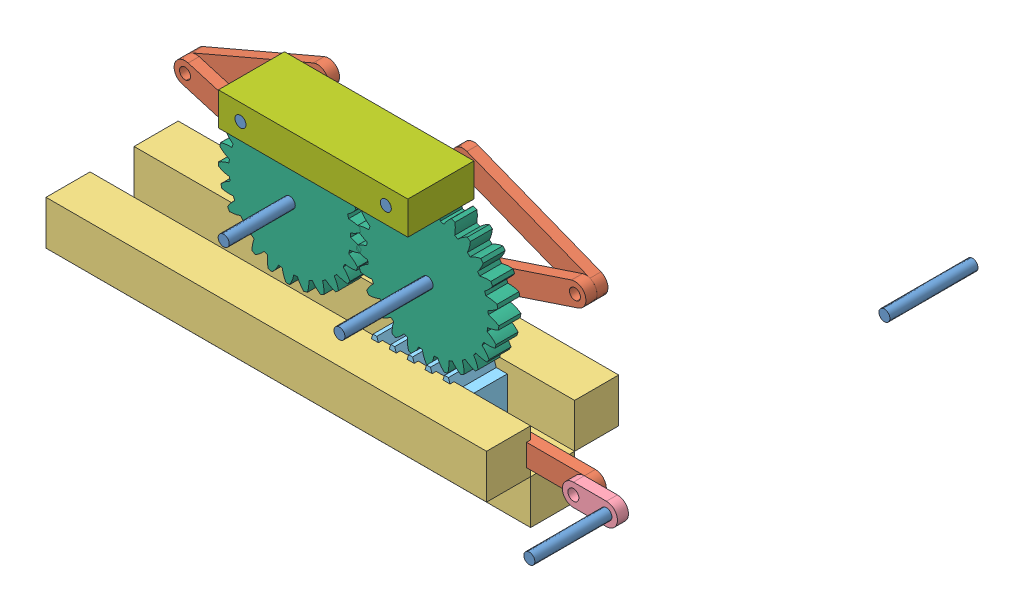
SolidWorks assembly assembly1, configuration Default. Lengths in mm.
Overall size (426.89 177.01 138.77).
17 component instances, 7 part files, 23 mates.
Components (placement in the parent):
- joint_1-1: joint_1 [Default] at (-55.7079 602.4272 -213.8227) x (-0.185168 0.982707 0) z (0 0 -1) size (6.35 6.35 50.8)
- LINK_4-1: LINK_4 [Default] at (-191.5162 473.0256 -183.0038) x (-1 0.000971 0) z (0 0 1) size (88.9 12.7 6.35)
- joint_1-2: joint_1 [Default] at (-172.4724 466.6561 -176.6538) x (-0.995124 -0.09863 0) z (0 0 1) size (6.35 6.35 50.8)
- platform_1-1: platform_1 [Default] at (-478.8705 454.5203 -229.7868) x (0 0 1) z (-0.000738 1 0) size (76.2 254 50.8)
- LINK_4-2: LINK_4 [Default] at (-216.1405 538.28 -199.8563) x (-0.930981 0.365067 0) z (0 0 -1) size (88.9 12.7 6.35)
- LINK_4-3: LINK_4 [Default] at (-441.1342 547.8007 -199.8563) x (0.919324 0.393502 0) z (0 0 -1) size (88.9 12.7 6.35)
- LINK_4-4: LINK_4 [Default] at (-211.8174 538.1665 -193.5063) x (-0.948848 -0.315733 0) z (0 0 -1) size (88.9 12.7 6.35)
- LINK_4-5: LINK_4 [Default] at (-440.4322 535.8725 -199.8563) x (0.959139 -0.282937 0) z (0 0 1) size (88.9 12.7 6.35)
- joint_1-4: joint_1 [Default] at (-365.5491 520.4032 -193.5063) x (0.131558 0.991308 0) z (0 0 1) size (6.35 6.35 50.8)
- joint_1-5: joint_1 [Default] at (-286.1245 520.1328 -180.8063) x (0.649611 0.760266 0) z (0 0 1) size (6.35 6.35 50.8)
- joint_1-6: joint_1 [Default] at (-284.7631 572.0098 -206.2063) x (0.531975 -0.84676 0) z (0 0 1) size (6.35 6.35 50.8)
- joint_1-8: joint_1 [Default] at (-368.583 571.9479 -206.2063) x (0.538835 -0.842411 0) z (0 0 1) size (6.35 6.35 50.8)
- LINK crank_1-2: LINK crank_1 [Default] at (-191.5158 473.0256 -170.3038) x (0.999999 -0.001025 0) z (0 0 -1) size (31.75 12.7 6.35)
- 2 g rack-2: 2 g rack [Default] at (-255.02 454.6856 -176.6538) x (-1 -0.000738 0) z (0 0 -1) size (57.15 28.15 25.4)
- gear new1-1: gear new1 [Default] at (-365.5491 520.4032 -180.8063) x (-0.514078 0.857744 0) z (0 0 -1) size (82.17 82.02 12.7)
- gear new1-2: gear new1 [Default] at (-286.1245 520.1328 -180.8063) x (0.174544 0.984649 0) z (0 0 -1) size (82.17 82.02 12.7)
- lifting-1: lifting [Default] at (-381.276 562.4135 -193.5063) x (1 0.000738 0) z (0 0 1) size (109.22 19.05 38.1)
Mates (geometry in assembly coordinates):
- Coincident17: coincident aligned: circle of LINK_4-2; circle of LINK_4-4
- Coincident19: coincident anti-aligned: circle of LINK_4-3; circle of joint_1-8
- Coincident20: coincident anti-aligned: circle of LINK_4-2; circle of joint_1-6
- Coincident59: coincident anti-aligned: circle of joint_1-2; circle of LINK crank_1-2
- Coincident60: coincident aligned: cylinder of LINK_4-1; cylinder of LINK crank_1-2 through (-191.5224 466.6757 -176.6538) axis (0 0 1) radius 3.175
- Coincident69: coincident anti-aligned: plane of LINK_4-1 through (-191.5161 473.0248 -176.6538) normal (0 0 1); plane of LINK crank_1-2 through (-191.5161 473.0248 -176.6538) normal (0 0 -1)
- Coincident82: coincident anti-aligned: circle of LINK_4-3; circle of LINK_4-5
- Coincident83: coincident anti-aligned: circle of joint_1-4; circle of gear new1-1
- Coincident84: coincident anti-aligned: circle of joint_1-5; circle of gear new1-2
- Coincident85: coincident anti-aligned: circle of LINK_4-1; circle of 2 g rack-2
- Coincident86: coincident anti-aligned: plane of platform_1-1 through (-478.8705 454.5203 -229.7868) normal (-0.000738 1 0); plane of 2 g rack-2 through (-255.02 454.6856 -202.0538) normal (0.000738 -1 0)
- Coincident87: coincident aligned: circle of LINK_4-4; circle of gear new1-2
- Coincident93: coincident aligned: circle of joint_1-8; circle of lifting-1
- Coincident94: coincident aligned: circle of joint_1-6; circle of lifting-1
- Coincident95: coincident aligned: plane of joint_1-8 through (-368.583 571.9479 -155.4063) normal (0 0 1); plane of lifting-1 through (-381.276 562.4135 -155.4063) normal (0 0 1)
- Coincident96: coincident aligned: plane of joint_1-6 through (-284.7631 572.0098 -155.4063) normal (0 0 1); plane of lifting-1 through (-381.276 562.4135 -155.4063) normal (0 0 1)
- Parallel1: parallel aligned: plane of gear new1-1 through (-365.5491 520.4032 -180.8063) normal (0 0 1); plane of gear new1-2 through (-286.1245 520.1328 -180.8063) normal (0 0 1)
- Parallel2: parallel aligned: plane of platform_1-1 through (-478.8892 479.9203 -229.7868) normal (-0.000738 1 0); plane of lifting-1 through (-381.2901 581.4635 -155.4063) normal (-0.000738 1 0)
- Coincident100: coincident aligned: circle of LINK_4-5; circle of joint_1-4
- RackPinionMate2: rack pinion = 64.6806 mm: line of 2 g rack-2 through (-312.3239 482.7976 -176.6538) axis (1 0.000738 0); circle of gear new1-2
- GearMate2: gear = 70.1802 : 70.1802 mm: circle of gear new1-1; circle of gear new1-2
- Coincident104: coincident: line of LINK_4-4 through (-288.1294 526.158 -193.5063) axis (0.948848 0.315733 0); point of gear new1-2
- Coincident105: coincident: line of LINK_4-5 through (-363.7525 526.4938 -193.5063) axis (-0.959139 0.282937 0); point of gear new1-1
